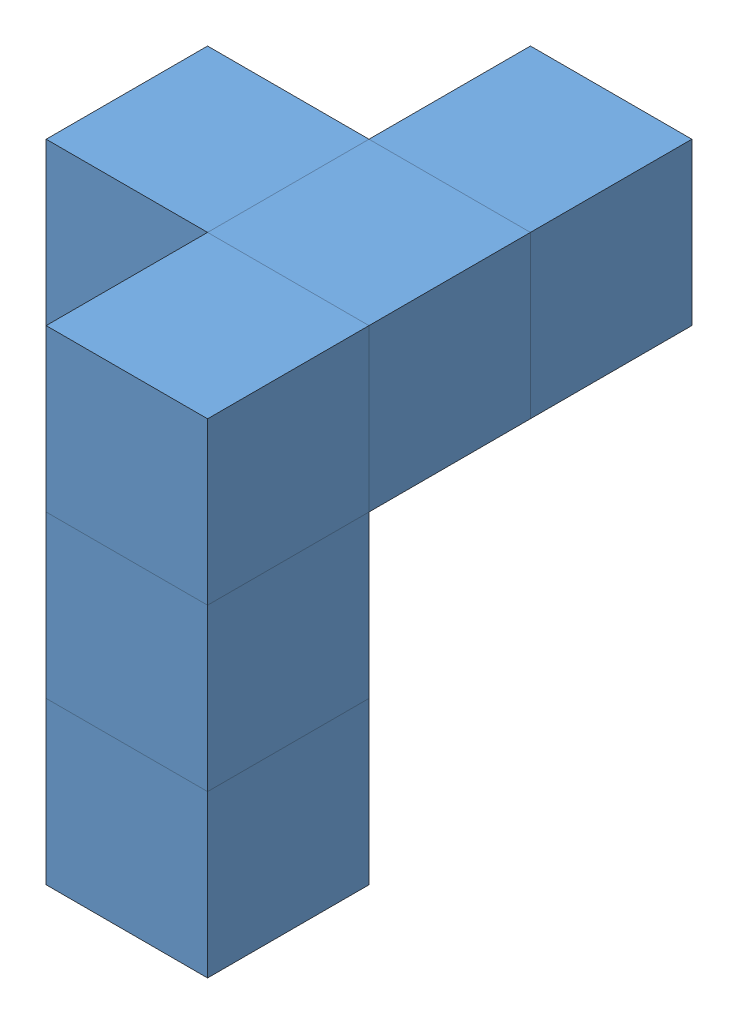
SolidWorks assembly Orange Piece, configuration Default. Lengths in mm.
Overall size (40 60 60).
6 component instances, 1 part files, 16 mates.
Components (placement in the parent):
- cube-1: cube [Default] at origin size (20 20 20)
- cube-2: cube [Default] at (0 20 0) size (20 20 20)
- cube-3: cube [Default] at (0 -20 0) size (20 20 20)
- cube-4: cube [Default] at (0 20 -40) size (20 20 20)
- cube-5: cube [Default] at (0 20 -20) x (0 0 1) z (-1 0 0) size (20 20 20)
- cube-6: cube [Default] at (-20 20 -20) size (20 20 20)
Mates (geometry in assembly coordinates):
- Coincident1: coincident anti-aligned: plane of cube-1 through (0 20 0) normal (0 1 0); plane of cube-2 through (0 20 0) normal (0 -1 0)
- Coincident2: coincident aligned: plane of cube-1 through (10 20 10) normal (0 0 1); plane of cube-2 through (10 40 10) normal (0 0 1)
- Coincident3: coincident aligned: plane of cube-1 through (-10 20 10) normal (-1 0 0); plane of cube-2 through (-10 40 10) normal (-1 0 0)
- Coincident4: coincident aligned: plane of cube-1 through (10 20 10) normal (0 0 1); plane of cube-3 through (10 0 10) normal (0 0 1)
- Coincident5: coincident anti-aligned: plane of cube-1 through (0 0 0) normal (0 -1 0); plane of cube-3 through (0 0 0) normal (0 1 0)
- Coincident6: coincident aligned: plane of cube-1 through (10 20 10) normal (0 0 1); plane of cube-3 through (10 0 10) normal (0 0 1)
- Coincident7: coincident aligned: plane of cube-1 through (10 20 10) normal (1 0 0); plane of cube-3 through (10 0 10) normal (1 0 0)
- Coincident8: coincident anti-aligned: plane of cube-2 through (10 40 -10) normal (0 0 -1); plane of cube-5 through (-10 40 -10) normal (0 0 1)
- Coincident9: coincident aligned: plane of cube-2 through (10 40 10) normal (1 0 0); plane of cube-5 through (10 40 -10) normal (1 0 0)
- Coincident10: coincident aligned: plane of cube-2 through (0 40 0) normal (0 1 0); plane of cube-5 through (0 40 -20) normal (0 1 0)
- Coincident11: coincident aligned: plane of cube-4 through (0 40 -40) normal (0 1 0); plane of cube-5 through (0 40 -20) normal (0 1 0)
- Coincident12: coincident aligned: plane of cube-4 through (10 40 -30) normal (1 0 0); plane of cube-5 through (10 40 -10) normal (1 0 0)
- Coincident13: coincident anti-aligned: plane of cube-4 through (10 40 -30) normal (0 0 1); plane of cube-5 through (-10 40 -30) normal (0 0 -1)
- Coincident14: coincident: plane of cube-5 through (-10 40 -10) normal (-1 0 0); plane of cube-6 through (-10 40 -10) normal (1 0 0)
- Coincident15: coincident: plane of cube-5 through (0 40 -20) normal (0 1 0); plane of cube-6 through (-20 40 -20) normal (0 1 0)
- Coincident17: coincident aligned: plane of cube-5 through (-10 40 -10) normal (0 0 1); plane of cube-6 through (-10 40 -10) normal (0 0 1)
